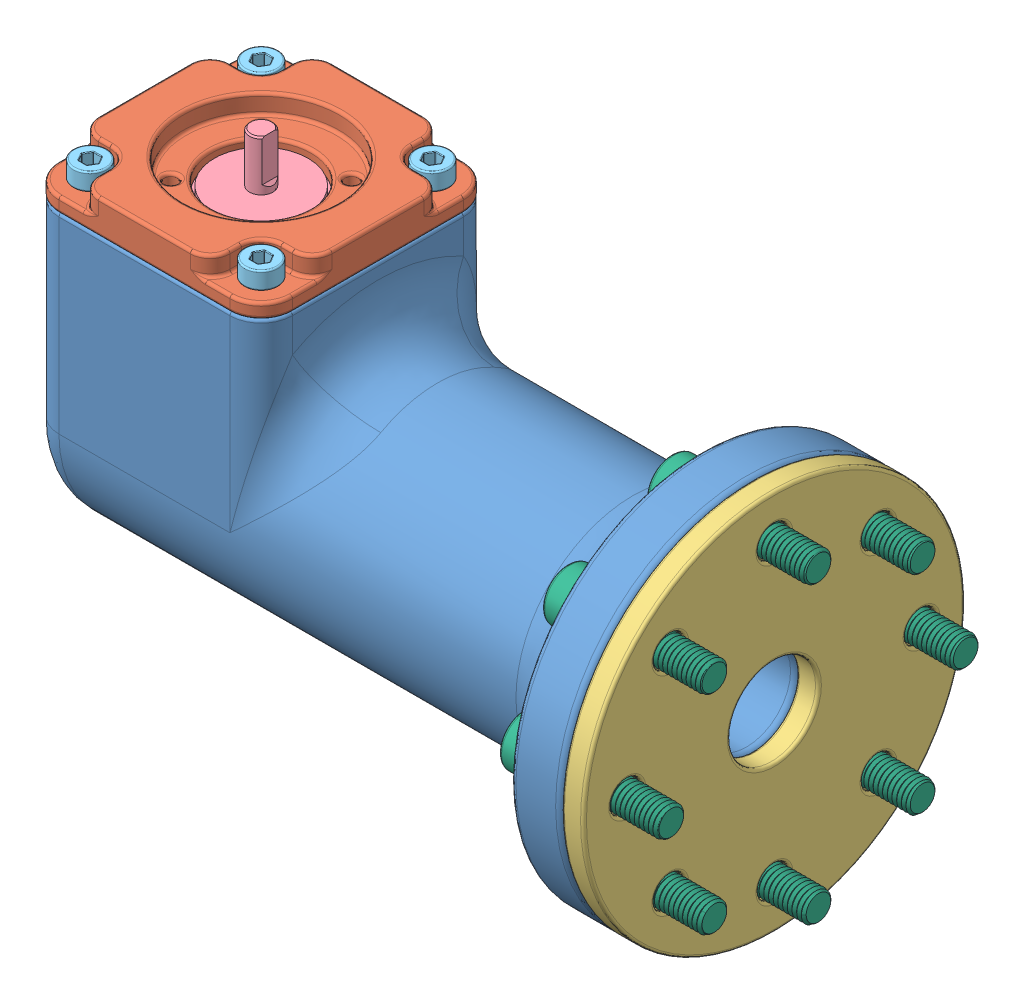
SolidWorks assembly Static_Arm_Assembly, configuration Default. Lengths in mm.
Overall size (115.55 75 65).
16 component instances, 6 part files, 20 mates.
Components (placement in the parent):
- Static_Prop_Arm-2: Static_Prop_Arm [Default] at (-9.129 54.138 80.415) x (0 -1 0) z (0 0 1) size (65 103.5 65)
- Prop_Top_Plate-1: Prop_Top_Plate [Default] at (-29.004 89.138 80.415) size (40.31 5.75 40.31)
- Static_Prop_Arm_Seal-1: Static_Prop_Arm_Seal [Default] at (56.496 54.138 80.415) x (0 1 0) z (0 0 1) size (65 3.75 65)
- Nema_8-1: Nema_8 [Default] at (-29.004 86.638 80.415) size (22 48 20)
- Prop_Plate_Bolt-1: Prop_Plate_Bolt [Default] at (-43.5665 92.138 94.9775) x (-1 0 0) z (0 0 1) size (5.75 19.35 5.75)
- Prop_Plate_Bolt-2: Prop_Plate_Bolt [Default] at (-43.5665 92.138 65.8525) x (-1 0 0) z (0 0 1) size (5.75 19.35 5.75)
- Prop_Plate_Bolt-3: Prop_Plate_Bolt [Default] at (-14.4415 92.138 65.8525) x (-1 0 0) z (0 0 1) size (5.75 19.35 5.75)
- Prop_Plate_Bolt-4: Prop_Plate_Bolt [Default] at (-14.4415 92.138 94.9775) x (-1 0 0) z (0 0 1) size (5.75 19.35 5.75)
- Mount_Bolt-1: Mount_Bolt [Default] at (40.871 79.2005 80.415) x (0 -1 0) z (0 0 1) size (8.75 25.52 8.75)
- Mount_Bolt-2: Mount_Bolt [Default] at (40.871 71.8599 98.1369) x (0 -0.707107 -0.707107) z (0 -0.707107 0.707107) size (8.75 25.52 8.75)
- Mount_Bolt-3: Mount_Bolt [Default] at (40.871 54.138 105.4775) x (0 0 -1) z (0 -1 0) size (8.75 25.52 8.75)
- Mount_Bolt-4: Mount_Bolt [Default] at (40.871 36.4162 98.1369) x (0 0.707107 -0.707107) z (0 -0.707107 -0.707107) size (8.75 25.52 8.75)
- Mount_Bolt-5: Mount_Bolt [Default] at (40.871 29.0755 80.415) x (0 1 0) z (0 0 -1) size (8.75 25.52 8.75)
- Mount_Bolt-6: Mount_Bolt [Default] at (40.871 36.4162 62.6932) x (0 0.707107 0.707107) z (0 0.707107 -0.707107) size (8.75 25.52 8.75)
- Mount_Bolt-7: Mount_Bolt [Default] at (40.871 54.138 55.3525) x (0 0 1) z (0 1 0) size (8.75 25.52 8.75)
- Mount_Bolt-8: Mount_Bolt [Default] at (40.871 71.8599 62.6932) x (0 -0.707107 0.707107) z (0 0.707107 0.707107) size (8.75 25.52 8.75)
Mates (geometry in assembly coordinates):
- Width3: width: plane of Prop_Top_Plate-1 through (-9.129 86.638 60.54) normal (1 0 0); plane of Prop_Top_Plate-1 through (-48.879 86.638 60.54) normal (-1 0 0); plane of Static_Prop_Arm-2 through (-17.754 7.3182 69.165) normal (-1 0 0); plane of Static_Prop_Arm-2 through (-40.254 7.3182 69.165) normal (1 0 0)
- Width4: width: plane of Prop_Top_Plate-1 through (-48.879 86.638 100.29) normal (0 0 1); plane of Prop_Top_Plate-1 through (-48.879 86.638 60.54) normal (0 0 -1); plane of Static_Prop_Arm-2 through (-40.254 7.3182 91.665) normal (0 0 -1); plane of Static_Prop_Arm-2 through (-40.254 7.3182 69.165) normal (0 0 1)
- Parallel1: parallel: plane of Static_Prop_Arm_Seal-1 through (56.496 54.138 80.415) normal (0 0 1); plane of assembly through (0 0 0) normal (0 0 1)
- Coincident4: coincident: plane of Static_Prop_Arm-2 through (54.621 54.138 80.415) normal (1 0 0); plane of Static_Prop_Arm_Seal-1 through (54.621 54.138 80.415) normal (-1 0 0)
- Concentric1: concentric: cylinder of Static_Prop_Arm-2 through (54.621 54.138 80.415) axis (-1 0 0) radius 7.5; cylinder of Static_Prop_Arm_Seal-1 through (58.371 54.138 80.415) axis (-1 0 0) radius 7.5
- Parallel2: parallel: plane of Static_Prop_Arm-2 through (-9.129 54.138 80.415) normal (0 0 1); plane of assembly through (0 0 0) normal (0 0 1)
- Coincident5: coincident: plane of Prop_Top_Plate-1 through (-29.004 86.638 80.415) normal (0 -1 0); plane of Nema_8-1 through (-29.004 86.638 80.415) normal (0 1 0)
- Concentric2: concentric: cylinder of Prop_Top_Plate-1 through (-29.004 86.638 80.415) axis (0 1 0) radius 8.5; cylinder of Nema_8-1 through (-29.004 88.138 80.415) axis (0 -1 0) radius 8
- Parallel3: parallel: plane of Nema_8-1 through (-19.004 48.638 90.415) normal (0 0 1); plane of assembly through (0 0 0) normal (0 0 1)
- Coincident13: coincident: plane of Prop_Top_Plate-1 through (-29.004 89.138 80.415) normal (0 1 0); plane of Prop_Plate_Bolt-1 through (-43.5665 89.138 94.9775) normal (0 -1 0)
- Concentric9: concentric: cylinder of Prop_Top_Plate-1 through (-43.5665 86.638 94.9775) axis (0 1 0) radius 1.6562; cylinder of Prop_Plate_Bolt-1 through (-43.5665 89.138 94.9775) axis (0 1 0) radius 2.875
- Coincident14: coincident: plane of Prop_Top_Plate-1 through (-29.004 89.138 80.415) normal (0 1 0); plane of Prop_Plate_Bolt-2 through (-43.5665 89.138 65.8525) normal (0 -1 0)
- Concentric10: concentric: cylinder of Prop_Top_Plate-1 through (-43.5665 86.638 65.8525) axis (0 1 0) radius 1.6562; cylinder of Prop_Plate_Bolt-2 through (-43.5665 89.138 65.8525) axis (0 1 0) radius 2.875
- Coincident15: coincident: plane of Prop_Top_Plate-1 through (-29.004 89.138 80.415) normal (0 1 0); plane of Prop_Plate_Bolt-3 through (-14.4415 89.138 65.8525) normal (0 -1 0)
- Coincident16: coincident: plane of Prop_Top_Plate-1 through (-29.004 89.138 80.415) normal (0 1 0); plane of Prop_Plate_Bolt-4 through (-14.4415 89.138 94.9775) normal (0 -1 0)
- Concentric11: concentric: cylinder of Prop_Top_Plate-1 through (-14.4415 86.638 65.8525) axis (0 1 0) radius 1.6562; cylinder of Prop_Plate_Bolt-3 through (-14.4415 89.138 65.8525) axis (0 1 0) radius 2.875
- Concentric13: concentric: cylinder of Prop_Top_Plate-1 through (-14.4415 86.638 94.9775) axis (0 1 0) radius 1.6562; cylinder of Prop_Plate_Bolt-4 through (-14.4415 89.138 94.9775) axis (0 1 0) radius 2.875
- Coincident17: coincident: plane of Static_Prop_Arm-2 through (45.871 79.2005 80.415) normal (-1 0 0); plane of Mount_Bolt-1 through (45.871 79.2005 80.415) normal (1 0 0)
- Concentric14: concentric: cylinder of Static_Prop_Arm-2 through (-16.642 79.2005 80.415) axis (1 0 0) radius 2.6562; cylinder of Mount_Bolt-1 through (45.871 79.2005 80.415) axis (-1 0 0) radius 4.375
- Coincident18: coincident: plane of Static_Prop_Arm-2 through (-48.879 86.638 100.29) normal (0 1 0); plane of Prop_Top_Plate-1 through (-29.004 86.638 80.415) normal (0 -1 0)
